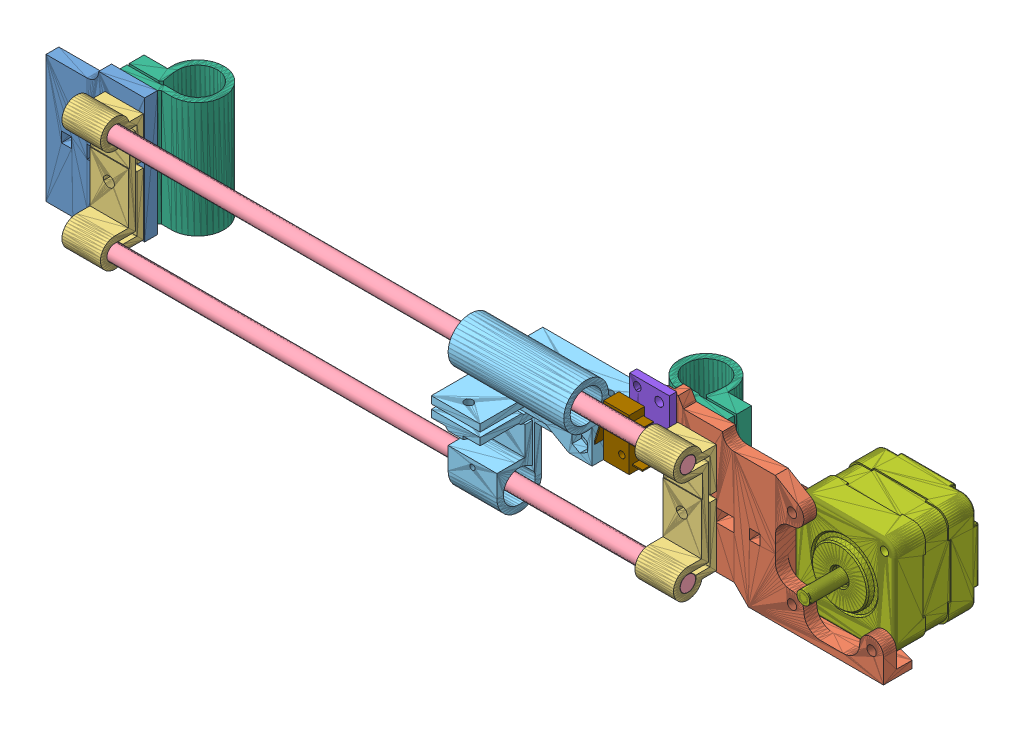
SolidWorks assembly carro x, configuration Valor predeterminado. Lengths in mm.
Overall size (326.09 60.01 64.36).
13 component instances, 9 part files, 28 mates.
Components (placement in the parent):
- x-end-idler-1: x-end-idler [Valor predeterminado] at (-222.5291 4.1513 0) x (-1 0 0) z (0 0 -1) size (38.54 54.1 21.59)
- x-end-motor-1: x-end-motor [Valor predeterminado] at (65.02 4.1513 0) x (-1 0 0) z (0 0 -1) size (87.52 57.61 21.59)
- x-rod-clamp-1: x-rod-clamp [Valor predeterminado] at (0 57.0613 0) x (0 -1 0) z (-1 0 0) size (51.22 16.72 15)
- x-rod-clamp-2: x-rod-clamp [Valor predeterminado] at (-223 57.0613 0) x (0 -1 0) z (-1 0 0) size (51.22 16.72 15)
- Barra lisa-1: Barra lisa [250 x 6mm] at (-238 51.4513 11.11) x (0 0 -1) z (1 0 0) size (6 6 238)
- Barra lisa-2: Barra lisa [250 x 6mm] at (-238 11.4513 11.11) x (0 0 -1) z (1 0 0) size (6 6 238)
- x-carriage-T2-5-1: x-carriage-T2-5 [Valor predeterminado] at (-84.612 2.7413 -17.0377) x (0 1 0) z (1 0 0) size (57.42 43.4 45)
- z-bearing-holder-1: z-bearing-holder [Valor predeterminado] at (-30.31 13.173 -5) x (1 0 0) z (0 1 0) size (29.52 21.21 45)
- z-bearing-holder-2: z-bearing-holder [Valor predeterminado] at (-207.69 58.2013 -5) x (-1 0 0) z (0 -1 0) size (29.52 21.21 45)
- NEMA17_33 MOTOR-1: NEMA17_33 MOTOR [Valor predeterminado] at (64.3804 9.4461 -38.0416) x (0 0 1) z (-1 0 0) size (49 39 39)
- subMontagem Xendstop-1: subMontagem Xendstop [Valor predeterminado] at (-33.81 62.7513 -9.4192) x (1 0 0) z (0 -1 0) size (26.56 8.95 32.95)
  - X-endstop-holder-1: X-endstop-holder [Valor predeterminado] at origin size (15.5 2.95 27)
  - chave microswitch 3T kw11-3z 5A-1: chave microswitch 3T kw11-3z 5A [Valor predeterminado] at (3.66 12.2292 18.4) x (0 0 -1) z (1 0 0) size (24.55 6 20.91)
Mates (geometry in assembly coordinates):
- Concêntrico9: concentric anti-aligned: circle of x-rod-clamp-1; cylinder of Barra lisa-1 through (0 51.4513 11.11) axis (-1 0 0) radius 3
- Coincidente4: coincident aligned: plane of x-rod-clamp-1 through (0 53.37 16.3817) normal (1 0 0); plane of Barra lisa-1 through (0 51.4513 11.11) normal (1 0 0)
- Concêntrico10: concentric anti-aligned: circle of x-rod-clamp-1; cylinder of Barra lisa-2 through (0 11.4513 11.11) axis (-1 0 0) radius 3
- Coincidente5: coincident aligned: plane of x-rod-clamp-1 through (0 10.913 14.1629) normal (1 0 0); plane of Barra lisa-2 through (0 11.4513 11.11) normal (1 0 0)
- Concêntrico11: concentric anti-aligned: circle of x-rod-clamp-2; cylinder of Barra lisa-2 through (0 11.4513 11.11) axis (-1 0 0) radius 3
- Concêntrico12: concentric anti-aligned: circle of x-rod-clamp-2; cylinder of Barra lisa-1 through (0 51.4513 11.11) axis (-1 0 0) radius 3
- Coincidente6: coincident aligned: plane of x-rod-clamp-2 through (-238 17.0613 5.81) normal (-1 0 0); plane of Barra lisa-2 through (-238 11.4513 11.11) normal (-1 0 0)
- Concêntrico13: concentric anti-aligned: cylinder of Barra lisa-1 through (0 51.4513 11.11) axis (-1 0 0) radius 3; circle of x-carriage-T2-5-1
- Concêntrico14: concentric anti-aligned: cylinder of Barra lisa-2 through (0 11.4513 11.11) axis (-1 0 0) radius 3; circle of x-carriage-T2-5-1
- Coincidente7: coincident anti-aligned: plane of x-rod-clamp-1 through (0 10.1913 0) normal (0 0 -1); plane of assembly through (0 0 0) normal (0 0 1)
- Coincidente8: coincident aligned: plane of x-rod-clamp-1 through (0 10.1913 0) normal (1 0 0); plane of assembly through (0 0 0) normal (1 0 0)
- Concêntrico15: concentric aligned: circle of x-end-motor-1; circle of x-rod-clamp-1
- Paralelo4: parallel aligned: plane of x-end-motor-1 through (-15.5 12.5013 -5) normal (-1 0 0); plane of x-rod-clamp-1 through (-15 17.0613 5.81) normal (-1 0 0)
- Concêntrico18: concentric aligned: circle of x-end-motor-1; circle of z-bearing-holder-1
- Coincidente10: coincident anti-aligned: plane of x-end-motor-1 through (2.4 58.2513 -5) normal (0 0 -1); plane of z-bearing-holder-1 through (-0.7934 58.173 -5) normal (0 0 1)
- Coincidente11: coincident anti-aligned: plane of x-end-motor-1 through (-12.8313 58.2513 0) normal (0 0 1); plane of x-rod-clamp-1 through (0 52.7113 0) normal (0 0 -1)
- Paralelo5: parallel aligned: plane of x-rod-clamp-1 through (0 48.3513 3.01) normal (1 0 0); plane of z-bearing-holder-1 through (-0.7934 58.173 -14.43) normal (1 0 0)
- Concêntrico21: concentric anti-aligned: circle of x-end-idler-1; circle of x-rod-clamp-2
- Paralelo6: parallel aligned: plane of x-end-idler-1 through (-222.5291 58.2513 0) normal (1 0 0); plane of x-rod-clamp-2 through (-223 34.4513 2.51) normal (1 0 0)
- Coincidente13: coincident anti-aligned: plane of x-end-idler-1 through (-222.5291 9.7013 0) normal (0 0 1); plane of x-rod-clamp-2 through (-223 10.1913 0) normal (0 0 -1)
- Concêntrico22: concentric aligned: circle of x-rod-clamp-2; circle of z-bearing-holder-2
- Paralelo7: parallel aligned: plane of x-end-idler-1 through (-260.9191 4.1513 0) normal (-1 0 0); plane of z-bearing-holder-2 through (-237.2066 13.2013 -14.43) normal (-1 0 0)
- Coincidente14: coincident anti-aligned: plane of x-end-idler-1 through (-222.5291 58.2513 -5) normal (0 0 -1); plane of z-bearing-holder-2 through (-237.2066 58.2013 -5) normal (0 0 1)
- Concêntrico23: concentric aligned: circle of x-end-motor-1; cylinder of NEMA17_33 MOTOR-1 through (29.3825 44.4493 -38) axis (0 0 1) radius 1.6
- Paralelo8: parallel aligned: plane of x-end-motor-1 through (65.02 4.1513 0) normal (1 0 0); plane of NEMA17_33 MOTOR-1 through (64.3798 18.4466 -27) normal (1 0 0)
- Coincidente16: coincident anti-aligned: plane of x-end-motor-1 through (61.0056 11.7598 -5) normal (0 0 -1); plane of NEMA17_33 MOTOR-1 through (63.3798 15.3966 -5) normal (0 0 1)
- Concêntrico24: concentric anti-aligned: circle of x-end-motor-1; cylinder of subMontagem Xendstop-1/X-endstop-holder-1 through (-19.5 58.7513 -10) axis (0 0 -1) radius 1.7
- Coincidente17: coincident anti-aligned: plane of x-end-motor-1 through (-19.5 53.226 0) normal (0 0 1); plane of subMontagem Xendstop-1/X-endstop-holder-1 through (-31 62.7513 0) normal (0 0 -1)
